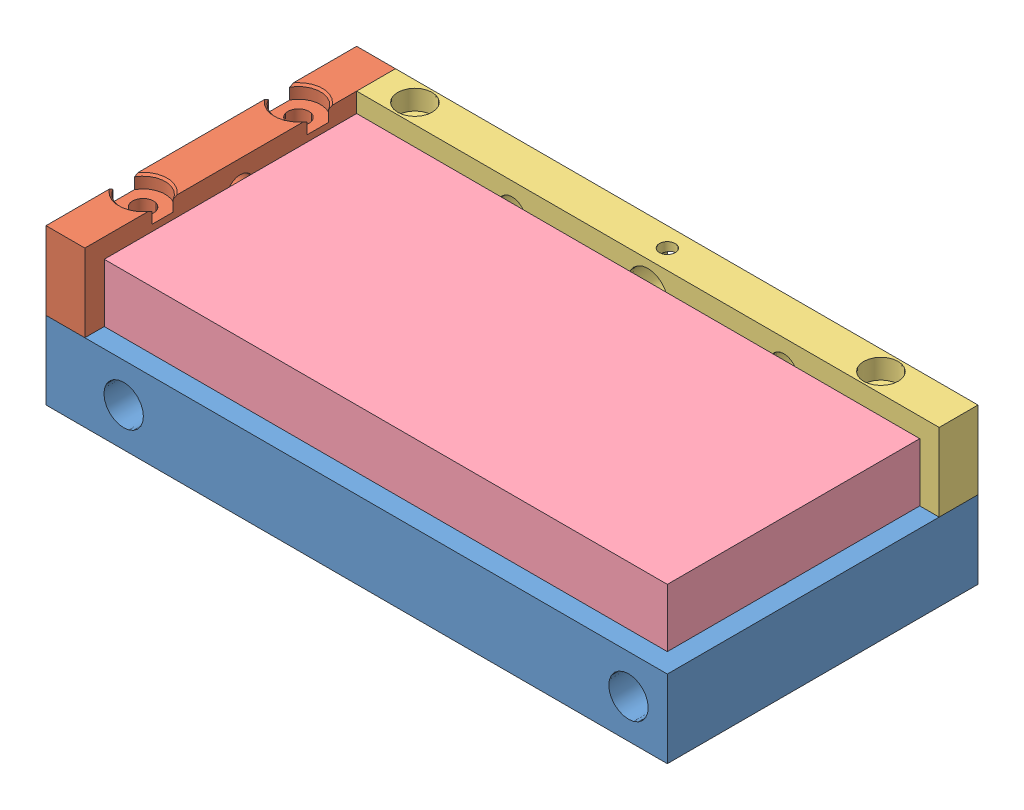
SolidWorks assembly stage, configuration Default. Lengths in mm.
Overall size (200 50 100).
7 component instances, 5 part files, 10 mates.
Components (placement in the parent):
- alignment_stage-1: alignment_stage [Default] at origin size (200 25 100)
- stage_rail-1: stage_rail [Default] at (-95.175 25 -32.0888) size (12.5 25 100)
- stage_side_rail_long-1: stage_side_rail_long [Default] at (84.9214 25 -42.9889) x (-1 0 0) z (0 0 -1) size (187.5 25 12.5)
- stage_plate-1: stage_plate [Default] at (-61.72 31.25 15.4833) x (0 0 -1) z (1 0 0) size (81.25 18.75 181.25)
- ceramic_ball_bearing-1: ceramic_ball_bearing [Default] at (87.5806 23.9986 5.9904) size (12.7 12.7 12.7)
- ceramic_ball_bearing-2: ceramic_ball_bearing [Default] at (-75.0021 25.057 -12.4627) size (12.7 12.7 12.7)
- ceramic_ball_bearing-3: ceramic_ball_bearing [Default] at (-75.1057 25.4796 25.0088) size (12.7 12.7 12.7)
Mates (geometry in assembly coordinates):
- Coincident1: coincident anti-aligned: plane of alignment_stage-1 through (0 25 0) normal (0 1 0); plane of stage_rail-1 through (-95.175 25 -32.0888) normal (0 -1 0)
- Coincident2: coincident aligned: line of alignment_stage-1 through (-100 25 50) axis (1 0 0); line of stage_rail-1 through (-100 25 50) axis (1 0 0)
- Concentric1: concentric aligned: circle of alignment_stage-1; circle of stage_rail-1
- Concentric2: concentric aligned: circle of alignment_stage-1; circle of stage_side_rail_long-1
- Concentric3: concentric aligned: circle of alignment_stage-1; circle of stage_side_rail_long-1
- Coincident3: coincident anti-aligned: plane of alignment_stage-1 through (0 25 0) normal (0 1 0); plane of stage_side_rail_long-1 through (84.9214 25 -42.9889) normal (0 -1 0)
- Parallel1: parallel anti-aligned: plane of stage_side_rail_long-1 through (100 50 -37.5) normal (0 0 1); plane of stage_plate-1 through (-81.25 50 -31.25) normal (0 0 -1)
- Coincident5: coincident aligned: plane of alignment_stage-1 through (-100 25 50) normal (0 0 1); plane of stage_plate-1 through (-81.25 50 50) normal (0 0 1)
- Coincident6: coincident aligned: plane of stage_side_rail_long-1 through (84.9214 50 -42.9889) normal (0 1 0); plane of stage_plate-1 through (-61.72 50 15.4833) normal (0 1 0)
- Coincident7: coincident aligned: plane of alignment_stage-1 through (100 25 -50) normal (1 0 0); plane of stage_plate-1 through (100 50 50) normal (1 0 0)
